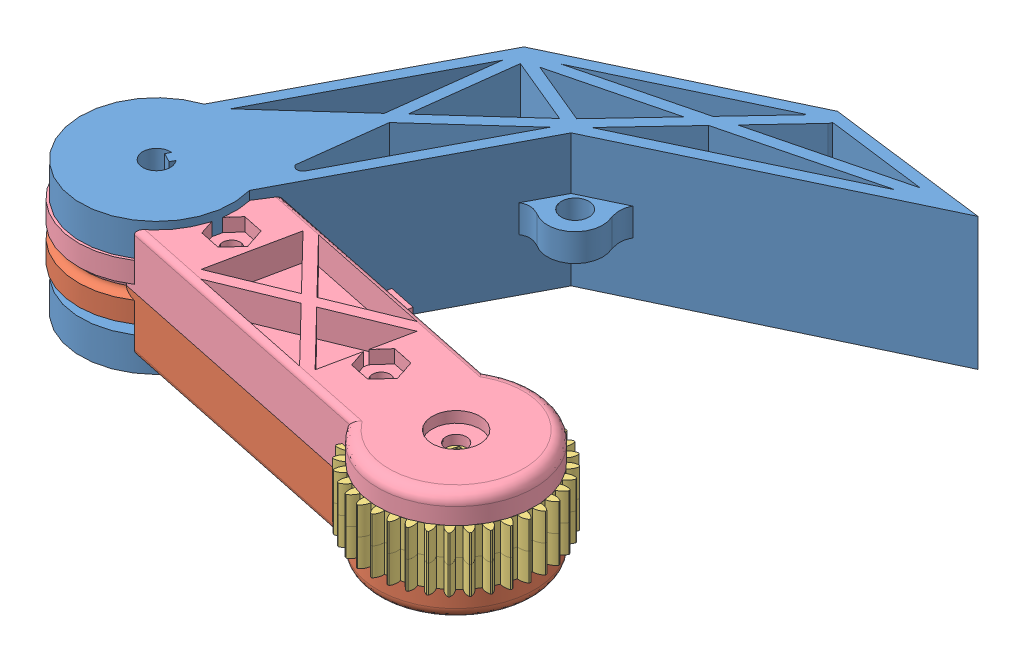
SolidWorks assembly Leg Assembly, configuration Default. Lengths in mm.
Overall size (136.45 30.48 160.94).
6 component instances, 4 part files, 6 mates.
Components (placement in the parent):
- FrontLowerLeg-1: FrontLowerLeg [Default] at (-95.9691 50.2896 -59.4311) x (0.460628 0 -0.887593) z (0.887593 0 0.460628) size (139.94 30.48 75.05)
- HalfDogBoneAssemblyt-2: HalfDogBoneAssemblyt [Default] at (-125.208 132.5786 107.7612) x (0.973037 0 0.230648) z (0.230648 0 -0.973037) size (127.44 25.58 41.09)
  - HalfDogBone-1: HalfDogBone [Default] at (58.483 65.7791 105.0954) x (0.999628 0 0.027267) z (-0.027267 0 0.999628) size (124.94 12.97 36.24)
  - 36tooth gear-3: 36tooth gear [Default] at (67.4563 68.9541 103.6194) x (0 0 1) z (0 1 0) size (40.08 40.08 9.53)
  - MirrorHalfDogBone-2: MirrorHalfDogBone [Default] at (58.483 65.7791 105.0954) x (0.999628 0 0.027267) z (0.027267 0 -0.999628) size (124.94 17.51 36.24)
  - 36tooth gear-4: 36tooth gear [Default] at (67.4563 62.6041 103.6194) x (0 0 1) z (0 1 0) size (40.08 40.08 9.53)
Mates (geometry in assembly coordinates):
- Concentric1: concentric anti-aligned: circle of ?; circle of ?
- Coincident2: coincident anti-aligned: plane of ? through (-127.8985 82.3448 -6.1667) normal (-0.042929 -0.998377 -0.03743); plane of ? through (-127.8985 82.3448 -6.1667) normal (0.042929 0.998377 0.03743)
- Coincident4: coincident anti-aligned: circle of ?; circle of FrontLowerLeg-1
- Coincident5: coincident anti-aligned: circle of FrontLowerLeg-1; circle of ?
- Concentric2: concentric anti-aligned: circle of FrontLowerLeg-1; circle of HalfDogBoneAssemblyt-2/MirrorHalfDogBone-2
- Coincident9: coincident anti-aligned: plane of FrontLowerLeg-1 through (-122.7009 73.1496 4.356) normal (0 -1 0); plane of HalfDogBoneAssemblyt-2/MirrorHalfDogBone-2 through (-122.7009 73.1496 4.356) normal (0 1 0)
